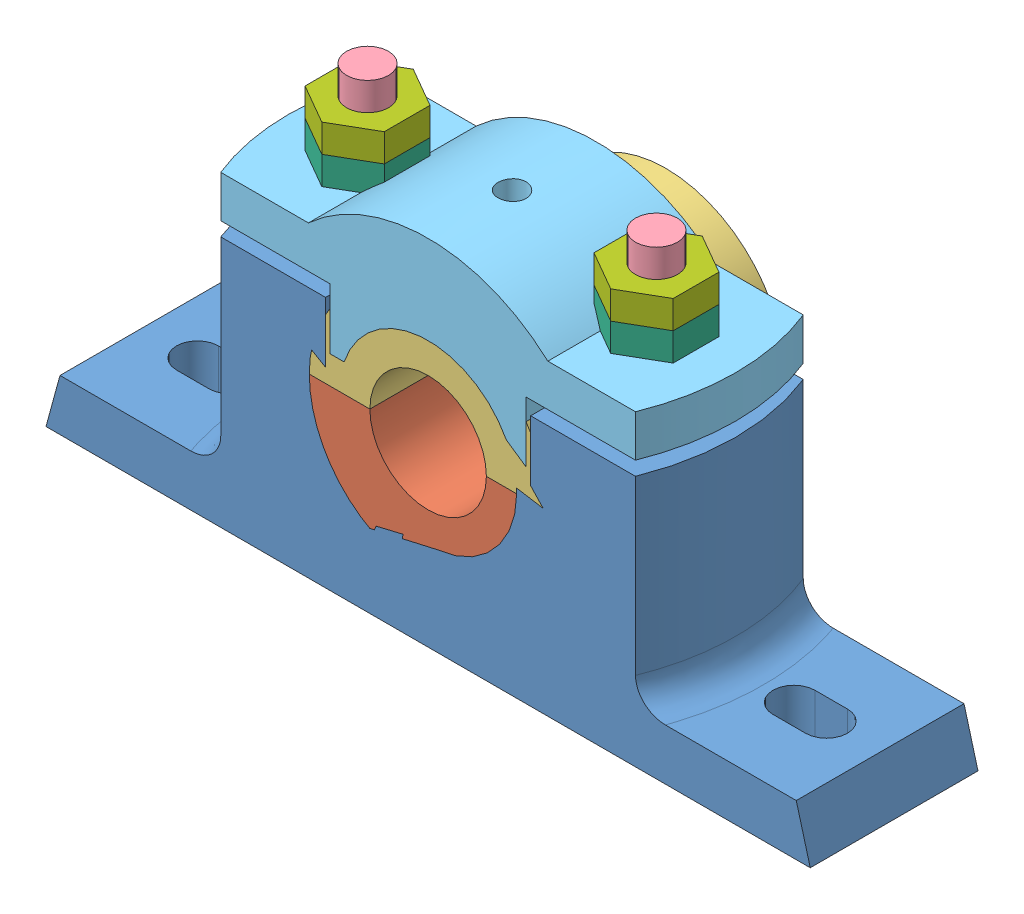
SolidWorks assembly Assem3, configuration Default. Lengths in mm.
Overall size (164 84 51).
10 component instances, 7 part files, 14 mates.
Components (placement in the parent):
- Casing-1: Casing [Default] at (62.4479 99.2954 127.3488) size (164 54 36)
- pp-1: pp [Default] at (62.4479 93.4719 119.8488) x (0 0 -1) z (1 0 0) size (51 25.5 51)
- pp1-3: pp1 [Default] at (62.4479 93.4719 119.8488) x (0 0 -1) z (1 0 0) size (51 25.5 51)
- bolt-1: bolt [Default] at (93.4479 63.4719 127.3488) x (-0.003665 0 -0.999993) z (-0.999993 0 0.003665) size (19 82 19)
- Cap-1: Cap [Default] at (62.4479 93.4719 127.3488) x (1 0 0) z (0 -1 0) size (96 36 32)
- lock Nut-1: lock Nut [Default] at (93.4479 121.4719 127.3488) size (17 6 19.63)
- Part 6-1: Part 6 [Default] at (93.4479 127.4719 127.3488) size (17 6 19.63)
- bolt-2: bolt [Default] at (31.4479 63.4719 127.3488) x (0.003665 0 -0.999993) z (-0.999993 0 -0.003665) size (19 82 19)
- Part 6-2: Part 6 [Default] at (31.4479 127.4719 127.3488) x (-1 0 0) z (0 0 -1) size (17 6 19.63)
- lock Nut-2: lock Nut [Default] at (31.4479 121.4719 127.3488) x (-1 0 0) z (0 0 -1) size (17 6 19.63)
Mates (geometry in assembly coordinates):
- Concentric1: concentric anti-aligned: cylinder of Casing-1 through (62.4479 93.4719 145.3488) axis (0 0 -1) radius 19; cylinder of pp-1 through (62.4479 93.4719 119.8488) axis (0 0 1) radius 17.5
- Coincident1: coincident aligned: plane of Casing-1 through (62.4479 93.4719 145.3488) normal (0 0 1); plane of pp-1 through (49.9479 93.4719 145.3488) normal (0 0 1)
- Coincident16: coincident anti-aligned: plane of pp-1 through (62.4479 93.4719 119.8488) normal (0 1 0); plane of pp1-3 through (62.4479 93.4719 119.8488) normal (0 -1 0)
- Coincident17: coincident aligned: plane of pp-1 through (49.9479 93.4719 94.3488) normal (0 0 -1); plane of pp1-3 through (74.9479 93.4719 94.3488) normal (0 0 -1)
- Concentric5: concentric aligned: cylinder of pp-1 through (62.4479 93.4719 119.8488) axis (0 0 1) radius 12.5; cylinder of pp1-3 through (62.4479 93.4719 119.8488) axis (0 0 1) radius 12.5
- Concentric6: concentric anti-aligned: cylinder of pp1-3 through (62.4479 93.4719 119.8488) axis (0 0 1) radius 19; cylinder of Cap-1 through (62.4479 93.4719 145.3488) axis (0 0 -1) radius 19
- Coincident18: coincident aligned: plane of pp1-3 through (74.9479 93.4719 145.3488) normal (0 0 1); plane of Cap-1 through (62.4479 93.4719 145.3488) normal (0 0 1)
- Coincident19: coincident anti-aligned: plane of Casing-1 through (62.4479 63.4719 127.3488) normal (0 -1 0); plane of bolt-1 through (93.4479 63.4719 127.3488) normal (0 1 0)
- Coincident26: coincident anti-aligned: plane of Casing-1 through (62.4479 63.4719 127.3488) normal (0 -1 0); plane of bolt-1 through (93.4479 63.4719 127.3488) normal (0 1 0)
- Concentric10: concentric anti-aligned: cylinder of Casing-1 through (93.4479 109.4719 127.3488) axis (0 1 0) radius 4.5; cylinder of bolt-1 through (93.4479 139.4719 127.3488) axis (0 -1 0) radius 4.5
- Concentric11: concentric anti-aligned: cylinder of bolt-1 through (93.4479 139.4719 127.3488) axis (0 -1 0) radius 4.5; cylinder of lock Nut-1 through (93.4479 121.4719 127.3488) axis (0 1 0) radius 4.5
- Coincident30: coincident anti-aligned: plane of Cap-1 through (88.1384 121.4719 145.3488) normal (0 1 0); plane of lock Nut-1 through (93.4479 121.4719 127.3488) normal (0 -1 0)
- Concentric12: concentric anti-aligned: cylinder of bolt-1 through (93.4479 139.4719 127.3488) axis (0 -1 0) radius 4.5; cylinder of Part 6-1 through (93.4479 127.4719 127.3488) axis (0 1 0) radius 4.5
- Coincident32: coincident anti-aligned: plane of lock Nut-1 through (93.4479 127.4719 127.3488) normal (0 1 0); plane of Part 6-1 through (93.4479 127.4719 127.3488) normal (0 -1 0)
